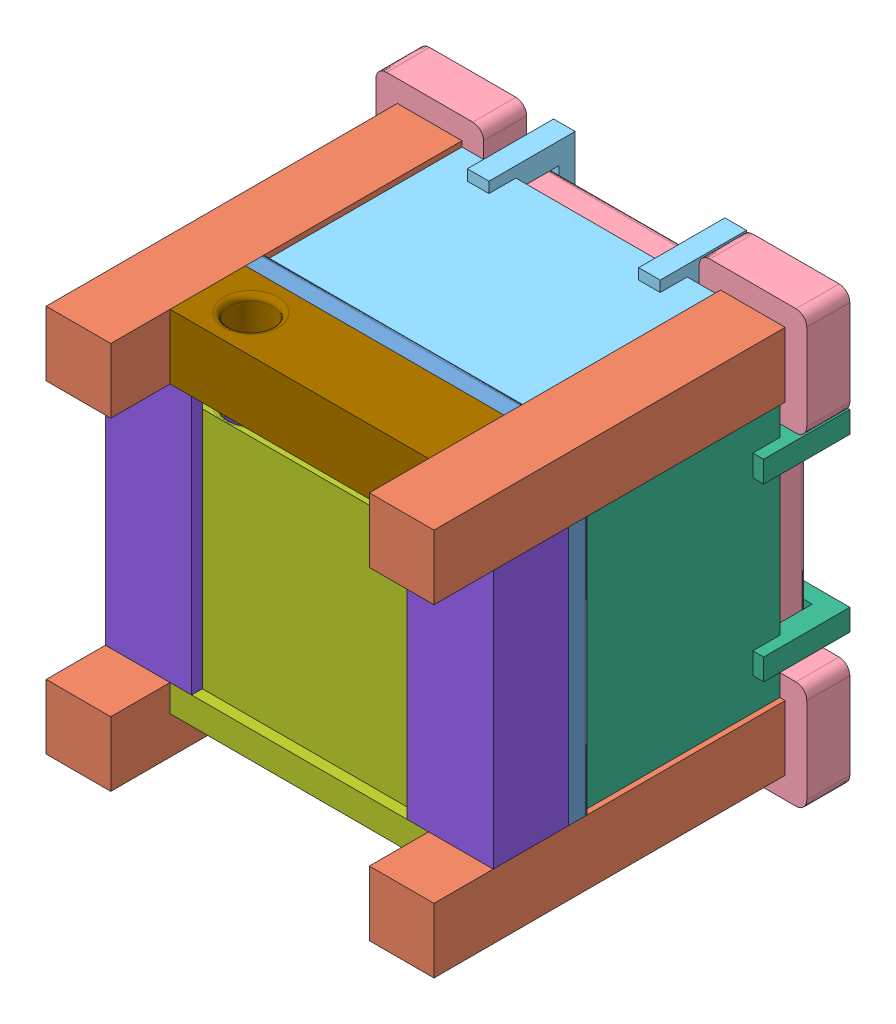
SolidWorks assembly Structure5, configuration Défaut. Lengths in mm.
Overall size (400 496.05 490.79).
18 component instances, 9 part files, 38 mates.
Components (placement in the parent):
- Platforme-1: Platforme [Défaut] at (202.4621 -173.2293 390) size (360 360 20)
- Patte-1: Patte [Défaut] at (142.4621 186.7707 495) x (-1 0 0) z (0 -1 0) size (60 350 60)
- Patte-2: Patte [Défaut] at (-157.5379 126.7707 495) x (0 -1 0) z (1 0 0) size (60 350 60)
- Patte-3: Patte [Défaut] at (-97.5379 -173.2293 495) x (1 0 0) z (0 1 0) size (60 350 60)
- Patte-4: Patte [Défaut] at (202.4621 -113.2293 495) x (0 1 0) z (-1 0 0) size (60 350 60)
- Pyramide-1: Pyramide [Défaut] at (38.5133 -317.4019 126.032) x (1 0 0) z (0 0.816497 0.57735) size (300 342.99 365.01)
  - FacePyramideFini-1: FacePyramideFini [Défaut] at (-21.8702 -119.0529 297.5) size (300 251.15 5)
  - FacePyramideFini-2: FacePyramideFini [Défaut] at (-166.0512 -29.0907 424.7257) x (0 -0.57735 -0.816497) z (0.816497 -0.471405 0.333333) size (300 251.15 5)
  - FacePyramideFini-3: FacePyramideFini [Défaut] at (133.9488 -35.8099 415.2233) x (0 0.57735 0.816497) z (-0.816497 -0.471405 0.333333) size (300 251.15 5)
  - FacePyramideFini-4: FacePyramideFini [Défaut] at (-10.2323 54.1522 542.449) x (-1 0 0) z (0 -0.942809 -0.333333) size (300 251.15 5)
- Socle2-1: Socle2 [Défaut] at (-94.2046 -63.7893 209) x (0 1 0) z (0 0 -1) size (400 400 40)
- FaceLarge-1: FaceLarge [Défaut] at (141.4621 181.7707 388) x (-1 0 0) z (0 -1 0) size (239 234 60)
- FaceCourte-1: FaceCourte [Défaut] at (-152.5379 125.7707 388) x (0 -1 0) z (1 0 0) size (239 234 60)
- FaceCourte-2: FaceCourte [Défaut] at (197.4621 -113.2293 388) x (0 1 0) z (-1 0 0) size (239 234 60)
- Tirroir-1: Tirroir [Défaut] at (142.4621 -128.2293 470) x (-1 0 0) z (0 -1 0) size (240 70 270.05)
- TirroirC-1: TirroirC [Défaut] at (202.4621 126.7707 480) x (-1 0 0) z (0 -1 0) size (80 70 240)
- TirroirC-2: TirroirC [Défaut] at (-157.5379 -113.2293 480) x (1 0 0) z (0 1 0) size (80 70 240)
- TirroirF-1: TirroirF [Défaut] at (-97.5379 186.7707 480) x (0 -1 0) z (1 0 0) size (60 70 240)
Mates (geometry in assembly coordinates):
- Coïncidente1: coincident anti-aligned: plane of Platforme-1 through (142.4621 186.7707 690) normal (1 0 0); plane of Patte-1 through (142.4621 126.7707 495) normal (-1 0 0)
- Coïncidente2: coincident anti-aligned: plane of Platforme-1 through (202.4621 126.7707 690) normal (0 1 0); plane of Patte-1 through (142.4621 126.7707 495) normal (0 -1 0)
- Coïncidente3: coincident: point of Platforme-1; point of Patte-1
- Coïncidente4: coincident anti-aligned: plane of Platforme-1 through (-157.5379 126.7707 690) normal (0 1 0); plane of Patte-2 through (-97.5379 126.7707 495) normal (0 -1 0)
- Coïncidente5: coincident anti-aligned: plane of Platforme-1 through (-97.5379 186.7707 690) normal (-1 0 0); plane of Patte-2 through (-97.5379 126.7707 495) normal (1 0 0)
- Coïncidente6: coincident: point of Platforme-1; point of Patte-2
- Coïncidente7: coincident anti-aligned: plane of Platforme-1 through (-97.5379 -173.2293 690) normal (-1 0 0); plane of Patte-3 through (-97.5379 -113.2293 495) normal (1 0 0)
- Coïncidente8: coincident anti-aligned: plane of Platforme-1 through (-157.5379 -113.2293 690) normal (0 -1 0); plane of Patte-3 through (-97.5379 -113.2293 495) normal (0 1 0)
- Coïncidente9: coincident: point of Platforme-1; point of Patte-3
- Coïncidente10: coincident anti-aligned: plane of Platforme-1 through (202.4621 -113.2293 690) normal (0 -1 0); plane of Patte-4 through (142.4621 -113.2293 495) normal (0 1 0)
- Coïncidente11: coincident anti-aligned: plane of Platforme-1 through (142.4621 -173.2293 690) normal (1 0 0); plane of Patte-4 through (142.4621 -113.2293 495) normal (-1 0 0)
- Coïncidente12: coincident: point of Platforme-1; point of Patte-4
- Coïncidente13: coincident anti-aligned: line of Platforme-1 through (-97.5379 156.7707 395) axis (1 0 0); line of Pyramide-1/FacePyramideFini-4 through (172.4621 156.7707 395) axis (-1 0 0)
- Coïncidente14: coincident anti-aligned: line of Platforme-1 through (-127.5379 -113.2293 395) axis (0 1 0); line of Pyramide-1/FacePyramideFini-2 through (-127.5379 156.7707 395) axis (0 -1 0)
- Coïncidente15: coincident anti-aligned: plane of Patte-1 through (142.4621 126.7707 189) normal (0 0 -1); plane of Socle2-1 through (-94.2046 -63.7893 189) normal (0 0 1)
- Coïncidente17: coincident anti-aligned: line of Patte-4 through (142.4621 -133.2293 189) axis (0 -1 0); line of Socle2-1 through (142.4621 -173.2293 189) axis (0 1 0)
- Coïncidente18: coincident aligned: line of Patte-4 through (162.4621 -113.2293 189) axis (1 0 0); line of Socle2-1 through (162.4621 -113.2293 189) axis (1 0 0)
- Coïncidente19: coincident anti-aligned: plane of Socle2-1 through (-94.2046 -63.7893 169) normal (0 0 -1); plane of FaceLarge-1 through (111.4621 131.7707 169) normal (0 0 1)
- Coïncidente20: coincident anti-aligned: plane of Socle2-1 through (122.4621 146.7707 189) normal (0 -1 0); plane of FaceLarge-1 through (111.4621 146.7707 184) normal (0 1 0)
- Coïncidente21: coincident anti-aligned: plane of Patte-2 through (-97.5379 126.7707 495) normal (1 0 0); plane of FaceLarge-1 through (-97.5379 171.7707 388) normal (-1 0 0)
- Coïncidente24: coincident anti-aligned: plane of Socle2-1 through (-94.2046 -63.7893 169) normal (0 0 -1); plane of FaceCourte-1 through (-102.5379 95.7707 169) normal (0 0 1)
- Coïncidente25: coincident anti-aligned: plane of Socle2-1 through (-117.5379 106.7707 189) normal (1 0 0); plane of FaceCourte-1 through (-117.5379 95.7707 184) normal (-1 0 0)
- Coïncidente26: coincident anti-aligned: plane of Patte-3 through (-97.5379 -113.2293 495) normal (0 1 0); plane of FaceCourte-1 through (-142.5379 -113.2293 388) normal (0 -1 0)
- Coïncidente27: coincident anti-aligned: plane of Socle2-1 through (-94.2046 -63.7893 169) normal (0 0 -1); plane of FaceCourte-2 through (147.4621 75.7707 169) normal (0 0 1)
- Coïncidente28: coincident anti-aligned: plane of Socle2-1 through (162.4621 -93.2293 189) normal (-1 0 0); plane of FaceCourte-2 through (162.4621 75.7707 184) normal (1 0 0)
- Coïncidente29: coincident anti-aligned: plane of Patte-4 through (142.4621 -113.2293 495) normal (0 1 0); plane of FaceCourte-2 through (187.4621 -113.2293 209) normal (0 -1 0)
- Coïncidente30: coincident anti-aligned: plane of Platforme-1 through (202.4621 -173.2293 410) normal (0 0 1); plane of TirroirC-2 through (-157.5379 126.7707 410) normal (0 0 -1)
- Coïncidente31: coincident aligned: plane of Platforme-1 through (-157.5379 186.7707 410) normal (-1 0 0); plane of TirroirC-2 through (-157.5379 126.7707 480) normal (-1 0 0)
- Coïncidente32: coincident anti-aligned: plane of Patte-2 through (-97.5379 126.7707 495) normal (0 -1 0); plane of TirroirC-2 through (-157.5379 126.7707 480) normal (0 1 0)
- Coïncidente33: coincident anti-aligned: plane of Platforme-1 through (202.4621 -173.2293 410) normal (0 0 1); plane of TirroirF-1 through (142.4621 186.7707 410) normal (0 0 -1)
- Coïncidente34: coincident aligned: plane of Platforme-1 through (-157.5379 186.7707 410) normal (0 1 0); plane of TirroirF-1 through (142.4621 186.7707 480) normal (0 1 0)
- Coïncidente35: coincident anti-aligned: plane of Patte-1 through (142.4621 126.7707 495) normal (-1 0 0); plane of TirroirF-1 through (142.4621 186.7707 480) normal (1 0 0)
- Coïncidente36: coincident anti-aligned: plane of Platforme-1 through (202.4621 -173.2293 410) normal (0 0 1); plane of TirroirC-1 through (202.4621 -113.2293 410) normal (0 0 -1)
- Coïncidente37: coincident aligned: plane of Platforme-1 through (202.4621 186.7707 410) normal (1 0 0); plane of TirroirC-1 through (202.4621 -113.2293 480) normal (1 0 0)
- Coïncidente38: coincident anti-aligned: plane of Patte-4 through (142.4621 -113.2293 495) normal (0 1 0); plane of TirroirC-1 through (202.4621 -113.2293 480) normal (0 -1 0)
- Coïncidente39: coincident anti-aligned: plane of Tirroir-1 through (142.4621 -138.2293 470) normal (0 0 1); plane of TirroirC-1 through (142.4621 -113.2293 470) normal (0 0 -1)
- Coïncidente40: coincident anti-aligned: plane of Tirroir-1 through (142.4621 -138.2293 470) normal (1 0 0); plane of TirroirC-1 through (142.4621 -113.2293 410) normal (-1 0 0)
- Coïncidente41: coincident anti-aligned: plane of Tirroir-1 through (-97.5379 -113.2293 470) normal (0 1 0); plane of TirroirC-1 through (202.4621 -113.2293 480) normal (0 -1 0)
